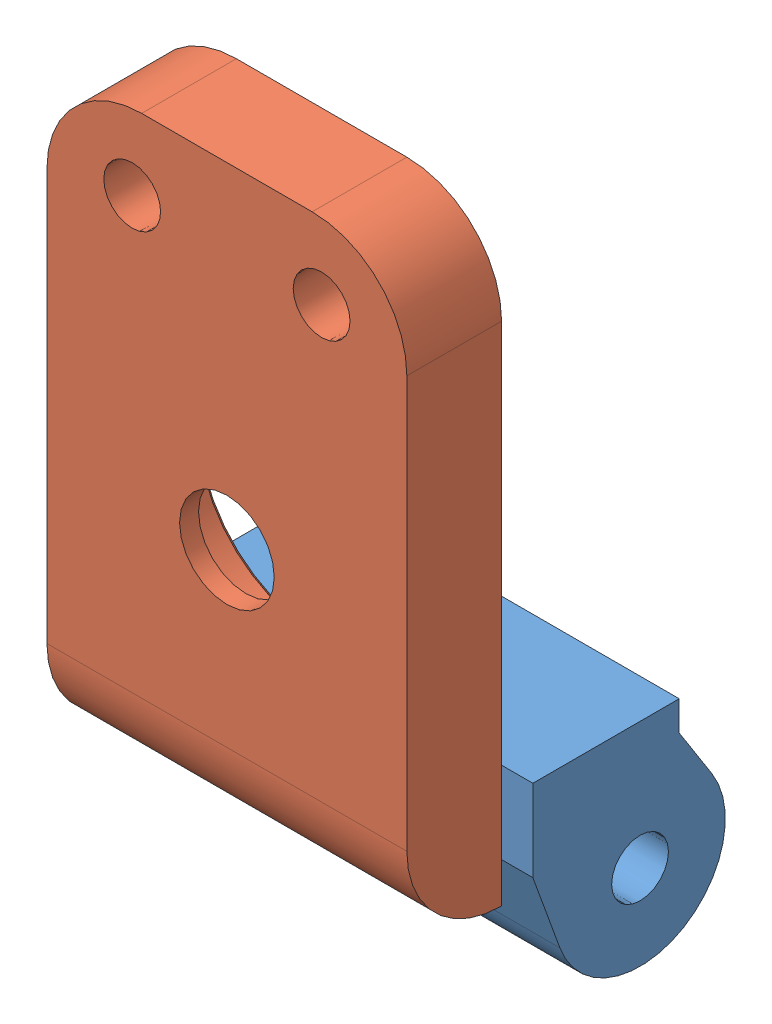
SolidWorks assembly shifterAssem trial, configuration Default. Lengths in mm.
Overall size (19 38.16 16.81).
3 component instances, 3 part files, 28 mates.
Components (placement in the parent):
- double main RJ final-1: double main RJ final [Default] at (-17.6871 -2.3749 -10.3603) size (52 29.55 28.96) (hidden)
- Shifter_Lever pivot RJ-1: Shifter_Lever pivot RJ [Default] at (12.7668 38.1968 17.4471) size (19 11.21 10.16)
- Shifter_Lever magnet RJ-1: Shifter_Lever magnet RJ [Default] at (12.7668 18.2015 18.9034) size (19 31.74 5)
Mates (geometry in assembly coordinates):
- Concentric1: concentric: cylinder of reach adjusted base-1 through (53.8786 15.3515 31.8077) axis (-1 0 0) radius 1.46; cylinder of Step_MS01_-_Shifter_Lever-1 through (55.1313 15.3515 31.8077) axis (-1 0 0) radius 1.5
- Coincident1: coincident: plane of reach adjusted base-1 through (47.3531 24.5378 36.9219) normal (-1 0 0); plane of Step_MS01_-_Shifter_Lever-1 through (47.3531 39.9282 34.9846) normal (1 0 0)
- Parallel1: parallel anti-aligned: plane of reach adjusted base-1 through (27.3531 23.8062 19.6615) normal (0 0 -1); plane of Step_MS01_-_Shifter_Lever-1 through (47.3531 45.8034 42.6615) normal (0 0 1)
- Concentric2: concentric: cylinder of reach adjusted base-1 through (53.8786 15.3515 31.8077) axis (-1 0 0) radius 1.46; cylinder of shift lever RJ-1/Shifter_Lever pivot RJ-1 through (55.1313 15.3515 31.8077) axis (-1 0 0) radius 1.5
- Coincident3: coincident anti-aligned: plane of reach adjusted base-1 through (47.3531 24.5378 36.9219) normal (-1 0 0); plane of shift lever RJ-1/Shifter_Lever pivot RJ-1 through (47.3531 39.9282 34.9846) normal (1 0 0)
- Coincident4: coincident: plane of reach adjusted base-1 through (13.3531 29.2168 53.084) normal (0 0 -1); plane of Shifter_Lever magnet RJ-1 through (22.2668 25.8081 44.1177) normal (0 0 1)
- Concentric3: concentric: cylinder of reach adjusted base-1 through (37.3531 31.0901 44.384) axis (0 0 1) radius 2.5; cylinder of Shifter_Lever magnet RJ-1 through (12.7668 31.3031 35.4177) axis (0 0 1) radius 2.5
- Parallel2: parallel aligned: plane of reach adjusted base-1 through (51.3531 34.4282 33.6615) normal (1 0 0); plane of Shifter_Lever magnet RJ-1 through (22.2668 19.9329 36.4408) normal (1 0 0)
- Concentric4: concentric aligned: cylinder of reach adjusted base-1 through (53.8786 15.3515 31.8077) axis (-1 0 0) radius 1.46; cylinder of Shifter_Lever pivot RJ-1 through (30.045 15.3515 31.8077) axis (-1 0 0) radius 1.5
- Distance1: distance = 0.5 mm anti-aligned: plane of Shifter_Lever pivot RJ-1 through (22.2668 39.9282 34.9846) normal (1 0 0); plane of reach adjusted base-1 through (47.3531 24.5378 36.9219) normal (-1 0 0)
- Parallel3: parallel aligned: plane of reach adjusted base-1 through (27.3531 33.9331 28.1317) normal (0 1 0); plane of Shifter_Lever pivot RJ-1 through (27.8531 20.4892 52.1827) normal (0 1 0)
- Concentric5: concentric aligned: cylinder of reach adjusted base-1 through (53.8786 15.3515 31.8077) axis (-1 0 0) radius 1.46; cylinder of Shifter_Lever reach adjusted final-1 through (54.6313 15.3515 31.8077) axis (-1 0 0) radius 1.5
- Distance2: distance = 0.5 mm anti-aligned: plane of Shifter_Lever reach adjusted final-1 through (46.8531 39.9282 34.9846) normal (1 0 0); plane of reach adjusted base-1 through (47.3531 24.5378 36.9219) normal (-1 0 0)
- Parallel4: parallel anti-aligned: plane of reach adjusted base-1 through (27.3531 23.8062 19.6615) normal (0 0 -1); plane of Shifter_Lever reach adjusted final-1 through (46.8531 25.5952 53.084) normal (0 0 1)
- Concentric6: concentric aligned: cylinder of reach adjusted base-1 through (53.8786 15.3515 31.8077) axis (-1 0 0) radius 1.46; cylinder of Shifter_Lever reach adjusted final2-1 through (54.6313 15.3515 31.8077) axis (-1 0 0) radius 1.5
- Distance3: distance = 0.5 mm anti-aligned: plane of Shifter_Lever reach adjusted final2-1 through (46.8531 39.9282 34.9846) normal (1 0 0); plane of reach adjusted base-1 through (47.3531 24.5378 36.9219) normal (-1 0 0)
- Concentric7: concentric aligned: cylinder of reach adjusted base-1 through (7.8786 15.3515 31.8077) axis (-1 0 0) radius 1.46; cylinder of shift lever RJ-2/Shifter_Lever pivot RJ-1 through (30.045 15.5644 22.8413) axis (-1 0 0) radius 1.5
- Distance4: distance = 0.5 mm anti-aligned: plane of shift lever RJ-2/Shifter_Lever pivot RJ-1 through (3.2668 40.1411 26.0182) normal (-1 0 0); plane of reach adjusted base-1 through (3.3531 24.5378 36.9219) normal (1 0 0)
- Concentric8: concentric aligned: cylinder of reach adjusted base-1 through (53.8786 15.3515 31.8077) axis (-1 0 0) radius 1.46; cylinder of Shifter_Lever reach adjusted final3-1 through (54.6313 15.3515 31.8077) axis (-1 0 0) radius 1.5
- Distance5: distance = 0.5 mm anti-aligned: plane of Shifter_Lever reach adjusted final3-1 through (46.8531 39.9282 34.9846) normal (1 0 0); plane of reach adjusted base-1 through (47.3531 24.5378 36.9219) normal (-1 0 0)
- Parallel5: parallel anti-aligned: plane of shift lever RJ-2/Shifter_Lever magnet RJ-1 through (22.2668 25.8081 44.1177) normal (0 0 1); plane of double main RJ final-1 through (2.7668 23.8062 19.6615) normal (0 0 -1)
- Coincident7: coincident anti-aligned: plane of shift lever RJ-2/Shifter_Lever magnet RJ-1 through (22.2668 25.8081 44.1177) normal (0 0 1); plane of double main RJ final-1 through (-11.2332 29.4298 44.1177) normal (0 0 -1)
- Concentric11: concentric aligned: cylinder of shift lever RJ-2/Shifter_Lever magnet RJ-1 through (12.7668 31.3031 35.4177) axis (0 0 1) radius 2.5; cylinder of double main RJ final-1 through (12.7668 31.3031 35.4177) axis (0 0 1) radius 2.5
- Coincident8: coincident anti-aligned: plane of double main RJ final-1 through (-11.2332 29.4298 44.1177) normal (0 0 -1); plane of Shifter_Lever magnet RJ-1 through (22.2668 25.8081 44.1177) normal (0 0 1)
- Concentric12: concentric aligned: cylinder of double main RJ final-1 through (12.7668 31.3031 35.4177) axis (0 0 1) radius 2.5; cylinder of Shifter_Lever magnet RJ-1 through (12.7668 31.3031 35.4177) axis (0 0 1) radius 2.5
- Concentric13: concentric aligned: cylinder of double main RJ final-1 through (29.2923 15.3515 31.8077) axis (-1 0 0) radius 1.46; cylinder of Shifter_Lever pivot RJ-1 through (30.045 15.3515 31.8077) axis (-1 0 0) radius 1.5
- Distance7: distance = 0.5 mm anti-aligned: plane of double main RJ final-1 through (22.7668 24.5378 36.9219) normal (-1 0 0); plane of Shifter_Lever pivot RJ-1 through (22.2668 39.9282 34.9846) normal (1 0 0)
- Parallel7: parallel aligned: plane of double main RJ final-1 through (2.7668 33.9331 28.1317) normal (0 1 0); plane of Shifter_Lever pivot RJ-1 through (3.2668 22.0579 56.7997) normal (0 1 0)
